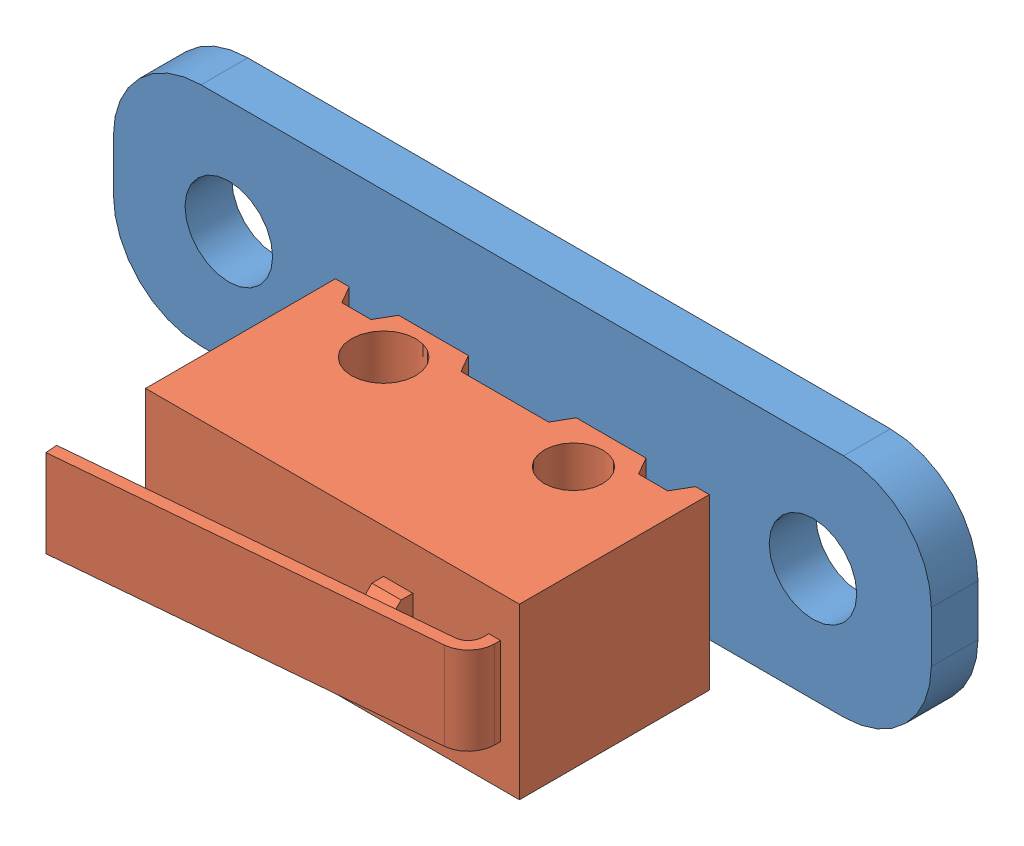
SolidWorks assembly Mechanical Switch, configuration Default. Lengths in mm.
Overall size (28 9.25 11.61).
2 component instances, 2 part files, 3 mates.
Components (placement in the parent):
- Switch-PCB-1: Switch-PCB [Default] at (-14.2864 3.7039 -0.8) size (28 7.75 1.6)
- D2F-Switch-1: D2F-Switch [Default] at (-14.2864 1.2289 2.3) x (1 0 0) z (0 -1 0) size (14.04 11.61 5.8)
Mates (geometry in assembly coordinates):
- Concentric1: concentric anti-aligned: circle of Switch-PCB-1; circle of D2F-Switch-1
- Concentric2: concentric anti-aligned: circle of Switch-PCB-1; circle of D2F-Switch-1
- Coincident1: coincident anti-aligned: plane of Switch-PCB-1 through (-14.2864 3.7039 0.8) normal (0 0 1); plane of D2F-Switch-1 through (-20.6864 -1.6711 0.8) normal (0 0 -1)
